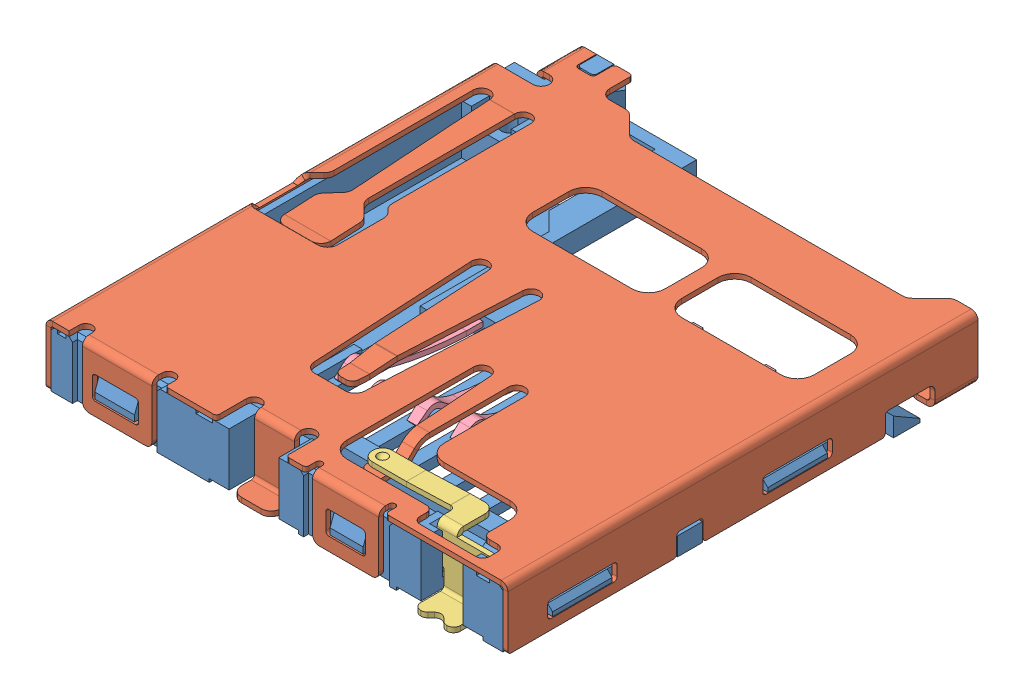
SolidWorks assembly microSD_Connector, configuration Default. Lengths in mm.
Overall size (14.1 2.14 15.45).
12 component instances, 5 part files, 11 mates.
Components (placement in the parent):
- microSD_Body-1: microSD_Body [Default] at origin size (14.1 1.85 15.2)
- microSD_Cover-1: microSD_Cover [Default] at (0 1.7 0) x (1 0 0) z (0 0 -1) size (13.95 1.9 15.2)
- microSD_Card_Detect-1: microSD_Card_Detect [Default] at (4.99 -0.05 7.4) size (4.45 1.9 2.05)
- microSD_Spring-2: microSD_Spring [Default] at (-3.85 1.125 6.9) x (-0.521999 -0.852946 0) z (0.852946 -0.521999 0) size (1.41 10.35 1.43) (hidden)
- microSD_Pin-1: microSD_Pin [11.15] at (5.725 -0.05 -2) x (0 0 1) z (-1 0 0) size (7.35 1.15 0.6)
- microSD_Pin-2: microSD_Pin [11.15] at (4.625 -0.05 -2) x (0 0 1) z (-1 0 0) size (7.35 1.15 0.6)
- microSD_Pin-3: microSD_Pin [11.35] at (3.525 -0.05 -2) x (0 0 1) z (-1 0 0) size (7.35 1.15 0.6)
- microSD_Pin-4: microSD_Pin [11.15] at (2.425 -0.05 -2) x (0 0 1) z (-1 0 0) size (7.35 1.15 0.6)
- microSD_Pin-5: microSD_Pin [11.35] at (1.325 -0.05 -2) x (0 0 1) z (-1 0 0) size (7.35 1.15 0.6)
- microSD_Pin-6: microSD_Pin [11.15] at (0.225 -0.05 -2) x (0 0 1) z (-1 0 0) size (7.35 1.15 0.6)
- microSD_Pin-7: microSD_Pin [10.75] at (-0.875 -0.05 -2) x (0 0 1) z (-1 0 0) size (7.25 1.15 0.6)
- microSD_Pin-8: microSD_Pin [11.15] at (-1.975 -0.05 -2) x (0 0 1) z (-1 0 0) size (7.35 1.15 0.6)
Mates (geometry in assembly coordinates):
- Coincident3: coincident anti-aligned: plane of microSD_Body-1 through (0 1.7 0) normal (0 1 0); plane of microSD_Cover-1 through (0 1.7 0) normal (0 -1 0)
- Coincident9: coincident anti-aligned: plane of microSD_Body-1 through (5.625 -0.001 6.8) normal (0 0 1); plane of microSD_Card_Detect-1 through (4.99 -0.05 6.8) normal (0 0 -1)
- Width5: width anti-aligned: plane of microSD_Body-1 through (4.355 -0.001 6.8) normal (1 0 0); plane of microSD_Body-1 through (5.625 -0.001 8.8) normal (-1 0 0); plane of microSD_Card_Detect-1 through (4.39 0.1 6.95) normal (-1 0 0); plane of microSD_Card_Detect-1 through (5.59 0.1 6.95) normal (1 0 0)
- Width6: width anti-aligned: plane of microSD_Body-1 through (-6.825 1.7 -7.6) normal (-1 0 0); plane of microSD_Body-1 through (6.825 1.7 -7.6) normal (1 0 0); plane of microSD_Cover-1 through (6.825 1.7 0) normal (-1 0 0); plane of microSD_Cover-1 through (-6.825 1.7 0) normal (1 0 0)
- Coincident11: coincident anti-aligned: plane of microSD_Body-1 through (0 0 7.45) normal (0 0 1); plane of microSD_Cover-1 through (0 1.7 7.45) normal (0 0 -1)
- Coincident12: coincident aligned: plane of microSD_Cover-1 through (0 1.85 0) normal (0 1 0); plane of microSD_Card_Detect-1 through (4.99 1.85 7.4) normal (0 1 0)
- Coincident13: coincident aligned: plane of microSD_Body-1 through (-4.725 -0.001 7) normal (0 0 -1); plane of microSD_Spring-2
- Concentric1: concentric: cylinder of microSD_Body-1 through (-3.85 1.125 5.5) axis (0 0 1) radius 0.275; point of microSD_Spring-2
- Coincident14: coincident: point of microSD_Body-1; point of microSD_Pin-1
- Coincident15: coincident: point of microSD_Body-1; point of microSD_Pin-1
- Coincident16: coincident anti-aligned: plane of microSD_Body-1 through (5.425 0.3 -7.601) normal (0 1 0); plane of microSD_Pin-1 through (5.425 0.3 -0.3) normal (0 -1 0)
